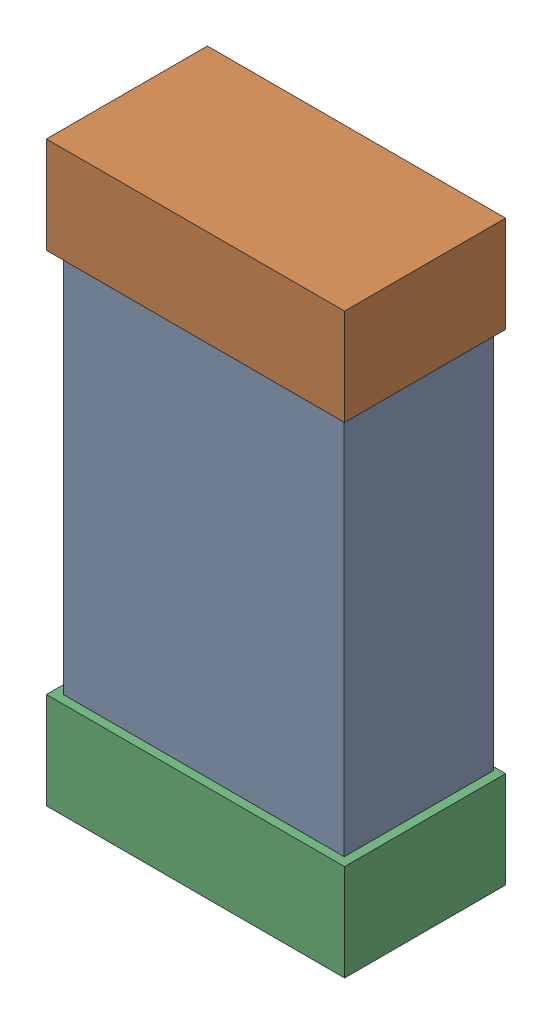
SolidWorks assembly C29, configuration Default. Lengths in mm.
Overall size (0.85 1.65 0.46).
6 component instances, 2 part files, 0 mates.
Components (placement in the parent):
- 432124816_39-1: 432124816_39 [Default] at (19.2999 40.4499 -0.8615) size (0.8 1.5 0.42)
  - Extruded (1)-1: Extruded (1) [Default] at origin size (0.8 1.5 0.42)
- 432138512_78-1: 432138512_78 [Default] at (19.2999 41.1357 -0.8715) size (0.85 0.28 0.46)
  - Extruded-1: Extruded [Default] at origin size (0.85 0.28 0.46)
- 432138512_79-1: 432138512_79 [Default] at (19.2999 39.7642 -0.8715) size (0.85 0.28 0.46)
  - Extruded-1: Extruded [Default] at origin size (0.85 0.28 0.46)
